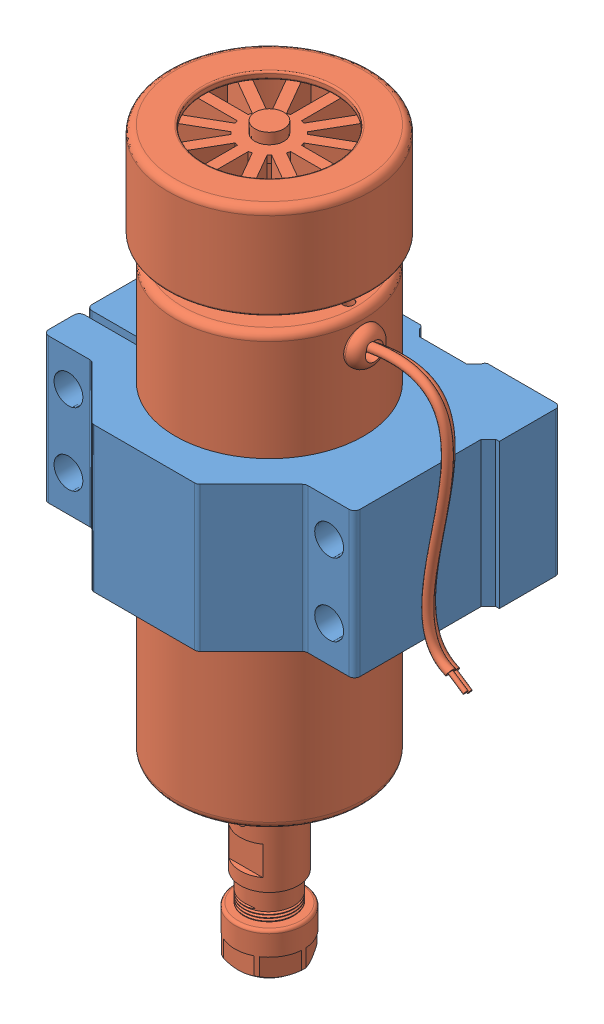
SolidWorks assembly Cabezal eje Z, configuration Predeterminado. Lengths in mm.
Overall size (100.46 200 69).
2 component instances, 2 part files, 3 mates.
Components (placement in the parent):
- soporte de fijacion spindle-1: soporte de fijacion spindle [Predeterminado] at (-9.3804 -16.7768 385) x (1 0 0) z (0 -1 0) size (91 69 40)
- Spindle Tupia ER11 Ø52 500W-1: Spindle Tupia ER11 Ø52 500W [Predeterminada] at (-9.3804 -46.2768 385) x (1 0 0) z (0 -1 0) size (83.46 56 200)
Mates (geometry in assembly coordinates):
- Concéntrica1: concentric: cylinder of ? through (-9.3804 -61.7768 385) axis (0 1 0) radius 26; cylinder of Spindle Tupia ER11 Ø52 500W-1 through (-9.3804 -105.7768 385) axis (0 1 0) radius 26
- Distancia2: distance = 30 mm: plane of assembly; plane of assembly; plane of Spindle Tupia ER11 Ø52 500W-1 through (-9.3804 13.2232 385) normal (0 1 0); plane of soporte de fijacion spindle-1 through (-9.3804 -16.7768 385) normal (0 1 0)
- Coincidente1: coincident: plane of ? through (-9.3804 -21.7768 385) normal (1 0 0); plane of Spindle Tupia ER11 Ø52 500W-1 through (-9.3804 -46.2768 385) normal (1 0 0)
